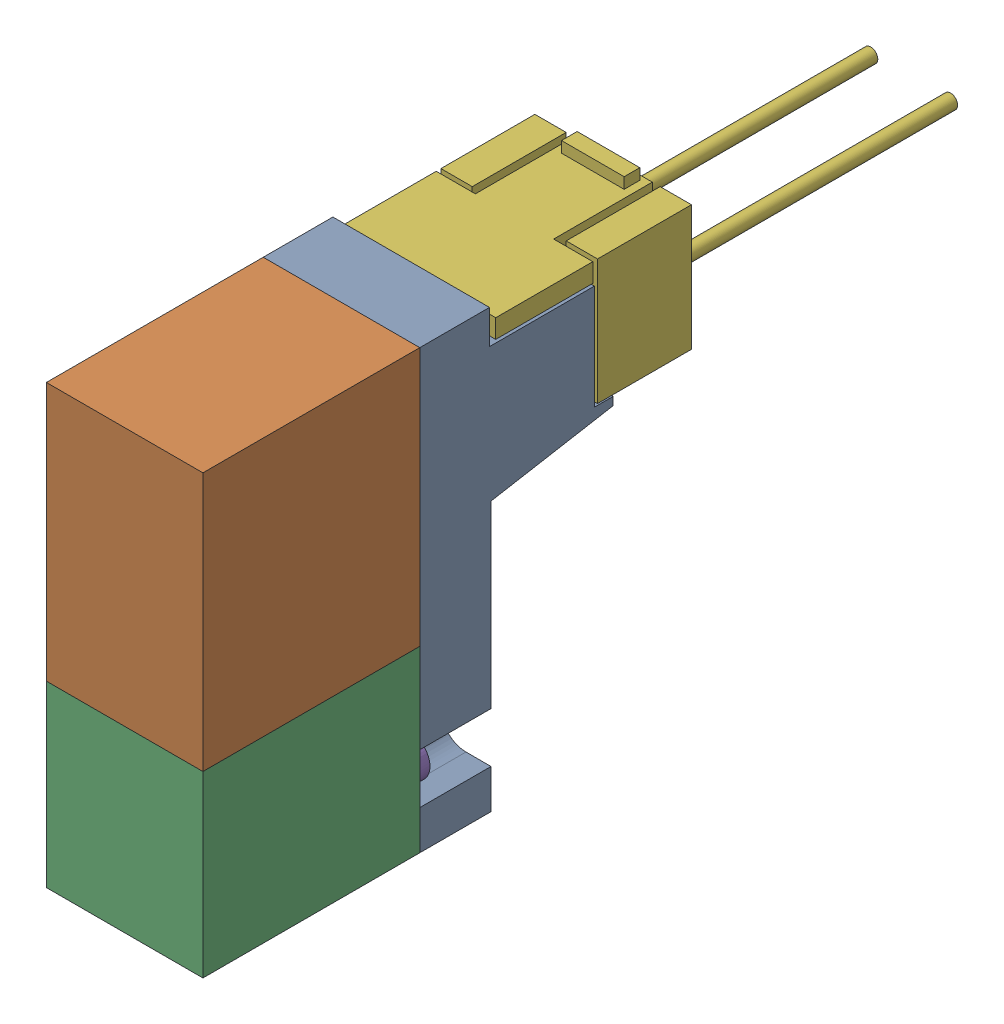
SolidWorks assembly 4GA120-M5-E01-4_D_100000_4G-Coil-SubASSY_01(EDC-E-H)-1, configuration Default. Lengths in mm.
Overall size (10 27.94 50.2).
2 component instances, 2 part files, 0 mates.
Components (placement in the parent):
- 4GA120-M5-E01-4_D_000102_4GcoilEDC_00(Default)-1: 4GA120-M5-E01-4_D_000102_4GcoilEDC_00(Default) [Default] at origin size (10 27.94 26.2)
- 4GA120-M5-E01-4_D_000123_4GSocketAssyE_00(Default)-1: 4GA120-M5-E01-4_D_000123_4GSocketAssyE_00(Default) [Default] at (0 22.17 -25.2) size (10 8.7 31.5)
